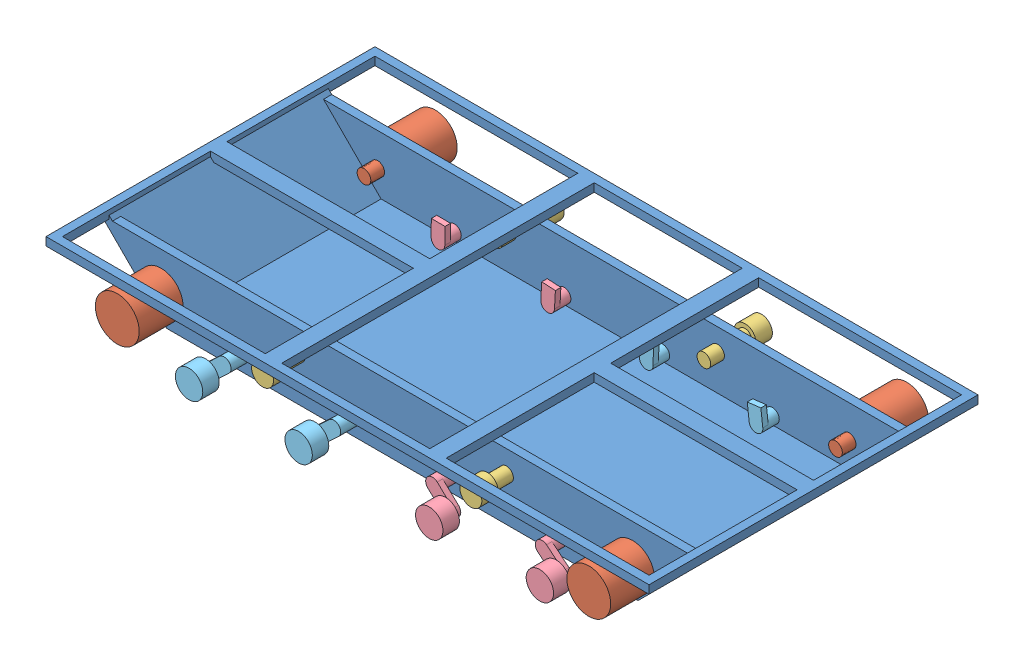
SolidWorks assembly Bodengruppe, configuration Standard. Lengths in mm.
Overall size (1100 159.37 600).
17 component instances, 5 part files, 32 mates.
Components (placement in the parent):
- Bodenwanne-1: Bodenwanne [Standard] at (-44.5526 57.4027 1100.0001) size (1100 135 600)
- Antriebsrolle-1: Antriebsrolle [Standard] at (-424.5526 -2.5973 1260.0001) x (0.031051 -0.999518 0) z (0 0 1) size (80 80 130)
- Antriebsrolle-2: Antriebsrolle [Standard] at (435.4474 -2.5973 1260.0001) x (0.999056 0.043432 0) z (0 0 1) size (80 80 130)
- Antriebsrolle-3: Antriebsrolle [Standard] at (-424.5526 -2.5973 940.0001) x (-0.898197 -0.439592 0) z (0 0 -1) size (80 80 130)
- Antriebsrolle-4: Antriebsrolle [Standard] at (435.4474 -2.5973 940.0001) x (-0.923728 -0.383049 0) z (0 0 -1) size (80 80 130)
- Führungsrolle-1: Führungsrolle [Standard] at (-184.5526 17.4027 1260.0001) x (0.998302 0.05825 0) z (0 0 1) size (40 40 105)
- Führungsrolle-2: Führungsrolle [Standard] at (195.4474 17.4027 1260.0001) x (0.998302 -0.05825 0) z (0 0 1) size (40 40 105)
- Führungsrolle-3: Führungsrolle [Standard] at (195.4474 17.4027 940.0001) x (-0.923728 -0.383049 0) z (0 0 -1) size (40 40 105)
- Führungsrolle-4: Führungsrolle [Standard] at (-184.5526 17.4027 940.0001) x (-0.923728 -0.383049 0) z (0 0 -1) size (40 40 105)
- Laufrolle-Rechts-1: Laufrolle-Rechts [Standard] at (95.4474 -32.5973 1265.0001) x (0.999622 0.027492 0) z (0 0 1) size (65.78 83.28 115)
- Laufrolle-Rechts-2: Laufrolle-Rechts [Standard] at (295.4474 -32.5973 1265.0001) x (0.995459 0.095187 0) z (0 0 1) size (65.78 83.28 115)
- Laufrolle-Rechts-3: Laufrolle-Rechts [Standard] at (-84.5526 -32.5973 935.0001) x (-0.998442 0.055805 0) z (0 0 -1) size (65.78 83.28 115)
- Laufrolle-Rechts-4: Laufrolle-Rechts [Standard] at (-284.5526 -32.5973 935.0001) x (-0.999954 0.009634 0) z (0 0 -1) size (65.78 83.28 115)
- Laufrolle-Links-1: Laufrolle-Links [Standard] at (-284.5526 -32.5973 1265.0001) x (0.999635 -0.027031 0) z (0 0 1) size (65.78 83.28 115)
- Laufrolle-Links-2: Laufrolle-Links [Standard] at (-84.5526 -32.5973 1265.0001) x (0.999467 -0.032641 0) z (0 0 1) size (65.78 83.28 115)
- Laufrolle-Links-3: Laufrolle-Links [Standard] at (95.4474 -32.5973 935.0001) x (-0.999945 0.010485 0) z (0 0 -1) size (65.78 83.28 115)
- Laufrolle-Links-4: Laufrolle-Links [Standard] at (295.4474 -32.5973 935.0001) x (-0.993247 -0.11602 0) z (0 0 -1) size (65.78 83.28 115)
Mates (geometry in assembly coordinates):
- Konzentrisch1: concentric anti-aligned: cylinder of Bodenwanne-1 through (-424.5526 -2.5973 855.0001) axis (0 0 1) radius 12.5; cylinder of Antriebsrolle-1 through (-424.5526 -2.5973 1310.0001) axis (0 0 -1) radius 12.5
- Abstand1: distance = 10 mm anti-aligned: plane of Antriebsrolle-1 through (-424.5526 -2.5973 1310.0001) normal (0 0 -1); plane of Bodenwanne-1 through (555.4474 -62.5973 1300.0001) normal (0 0 1)
- Konzentrisch2: concentric anti-aligned: cylinder of Bodenwanne-1 through (435.4474 -2.5973 855.0001) axis (0 0 1) radius 12.5; cylinder of Antriebsrolle-2 through (435.4474 -2.5973 1310.0001) axis (0 0 -1) radius 12.5
- Abstand2: distance = 10 mm anti-aligned: plane of Antriebsrolle-2 through (435.4474 -2.5973 1310.0001) normal (0 0 -1); plane of Bodenwanne-1 through (555.4474 -62.5973 1300.0001) normal (0 0 1)
- Konzentrisch3: concentric aligned: cylinder of Bodenwanne-1 through (-424.5526 -2.5973 855.0001) axis (0 0 1) radius 12.5; cylinder of Antriebsrolle-3 through (-424.5526 -2.5973 890.0001) axis (0 0 1) radius 12.5
- Abstand3: distance = 10 mm anti-aligned: plane of Antriebsrolle-3 through (-424.5526 -2.5973 890.0001) normal (0 0 1); plane of Bodenwanne-1 through (-544.5526 -62.5973 900.0001) normal (0 0 -1)
- Konzentrisch4: concentric aligned: cylinder of Bodenwanne-1 through (435.4474 -2.5973 855.0001) axis (0 0 1) radius 12.5; cylinder of Antriebsrolle-4 through (435.4474 -2.5973 890.0001) axis (0 0 1) radius 12.5
- Abstand4: distance = 10 mm anti-aligned: plane of Bodenwanne-1 through (-544.5526 -62.5973 900.0001) normal (0 0 -1); plane of Antriebsrolle-4 through (435.4474 -2.5973 890.0001) normal (0 0 1)
- Konzentrisch5: concentric anti-aligned: cylinder of Bodenwanne-1 through (-184.5526 17.4027 855.0001) axis (0 0 1) radius 12.5; cylinder of Führungsrolle-1 through (-184.5526 17.4027 1335.0001) axis (0 0 -1) radius 12.5
- Konzentrisch6: concentric anti-aligned: cylinder of Bodenwanne-1 through (195.4474 17.4027 855.0001) axis (0 0 1) radius 12.5; cylinder of Führungsrolle-2 through (195.4474 17.4027 1335.0001) axis (0 0 -1) radius 12.5
- Konzentrisch7: concentric aligned: cylinder of Bodenwanne-1 through (-184.5526 17.4027 855.0001) axis (0 0 1) radius 12.5; cylinder of Führungsrolle-4 through (-184.5526 17.4027 865.0001) axis (0 0 1) radius 12.5
- Konzentrisch8: concentric aligned: cylinder of Bodenwanne-1 through (195.4474 17.4027 855.0001) axis (0 0 1) radius 12.5; cylinder of Führungsrolle-3 through (195.4474 17.4027 865.0001) axis (0 0 1) radius 12.5
- Abstand5: distance = 35 mm anti-aligned: plane of Führungsrolle-3 through (195.4474 17.4027 865.0001) normal (0 0 1); plane of Bodenwanne-1 through (-544.5526 -62.5973 900.0001) normal (0 0 -1)
- Abstand6: distance = 35 mm anti-aligned: plane of Führungsrolle-4 through (-184.5526 17.4027 865.0001) normal (0 0 1); plane of Bodenwanne-1 through (-544.5526 -62.5973 900.0001) normal (0 0 -1)
- Abstand7: distance = 35 mm anti-aligned: plane of Führungsrolle-2 through (195.4474 17.4027 1335.0001) normal (0 0 -1); plane of Bodenwanne-1 through (555.4474 -62.5973 1300.0001) normal (0 0 1)
- Abstand8: distance = 35 mm anti-aligned: plane of Führungsrolle-1 through (-184.5526 17.4027 1335.0001) normal (0 0 -1); plane of Bodenwanne-1 through (555.4474 -62.5973 1300.0001) normal (0 0 1)
- Konzentrisch9: concentric anti-aligned: cylinder of Bodenwanne-1 through (-284.5526 -32.5973 855.0001) axis (0 0 1) radius 12.5; cylinder of Laufrolle-Links-1 through (-284.5526 -32.5973 1325.0001) axis (0 0 -1) radius 12.5
- Konzentrisch10: concentric anti-aligned: cylinder of Bodenwanne-1 through (-84.5526 -32.5973 855.0001) axis (0 0 1) radius 12.5; cylinder of Laufrolle-Links-2 through (-84.5526 -32.5973 1325.0001) axis (0 0 -1) radius 12.5
- Konzentrisch11: concentric anti-aligned: cylinder of Bodenwanne-1 through (95.4474 -32.5973 855.0001) axis (0 0 1) radius 12.5; cylinder of Laufrolle-Rechts-1 through (95.4474 -32.5973 1325.0001) axis (0 0 -1) radius 12.5
- Konzentrisch12: concentric anti-aligned: cylinder of Bodenwanne-1 through (295.4474 -32.5973 855.0001) axis (0 0 1) radius 12.5; cylinder of Laufrolle-Rechts-2 through (295.4474 -32.5973 1325.0001) axis (0 0 -1) radius 12.5
- Konzentrisch13: concentric aligned: cylinder of Bodenwanne-1 through (-284.5526 -32.5973 855.0001) axis (0 0 1) radius 12.5; cylinder of Laufrolle-Rechts-4 through (-284.5526 -32.5973 875.0001) axis (0 0 1) radius 12.5
- Konzentrisch14: concentric aligned: cylinder of Bodenwanne-1 through (-84.5526 -32.5973 855.0001) axis (0 0 1) radius 12.5; cylinder of Laufrolle-Rechts-3 through (-84.5526 -32.5973 875.0001) axis (0 0 1) radius 12.5
- Konzentrisch15: concentric aligned: cylinder of Bodenwanne-1 through (95.4474 -32.5973 855.0001) axis (0 0 1) radius 12.5; cylinder of Laufrolle-Links-3 through (95.4474 -32.5973 875.0001) axis (0 0 1) radius 12.5
- Konzentrisch16: concentric aligned: cylinder of Bodenwanne-1 through (295.4474 -32.5973 855.0001) axis (0 0 1) radius 12.5; cylinder of Laufrolle-Links-4 through (295.4474 -32.5973 875.0001) axis (0 0 1) radius 12.5
- Abstand9: distance = 25 mm anti-aligned: plane of Laufrolle-Links-1 through (-284.5526 -32.5973 1325.0001) normal (0 0 -1); plane of Bodenwanne-1 through (555.4474 -62.5973 1300.0001) normal (0 0 1)
- Abstand10: distance = 25 mm anti-aligned: plane of Laufrolle-Links-2 through (-84.5526 -32.5973 1325.0001) normal (0 0 -1); plane of Bodenwanne-1 through (555.4474 -62.5973 1300.0001) normal (0 0 1)
- Abstand11: distance = 25 mm anti-aligned: plane of Laufrolle-Rechts-1 through (95.4474 -32.5973 1325.0001) normal (0 0 -1); plane of Bodenwanne-1 through (555.4474 -62.5973 1300.0001) normal (0 0 1)
- Abstand12: distance = 25 mm anti-aligned: plane of Laufrolle-Rechts-2 through (295.4474 -32.5973 1325.0001) normal (0 0 -1); plane of Bodenwanne-1 through (555.4474 -62.5973 1300.0001) normal (0 0 1)
- Abstand13: distance = 25 mm anti-aligned: plane of Laufrolle-Links-4 through (295.4474 -32.5973 875.0001) normal (0 0 1); plane of Bodenwanne-1 through (-544.5526 -62.5973 900.0001) normal (0 0 -1)
- Abstand14: distance = 25 mm anti-aligned: plane of Laufrolle-Links-3 through (95.4474 -32.5973 875.0001) normal (0 0 1); plane of Bodenwanne-1 through (-544.5526 -62.5973 900.0001) normal (0 0 -1)
- Abstand15: distance = 25 mm anti-aligned: plane of Laufrolle-Rechts-3 through (-84.5526 -32.5973 875.0001) normal (0 0 1); plane of Bodenwanne-1 through (-544.5526 -62.5973 900.0001) normal (0 0 -1)
- Abstand16: distance = 25 mm anti-aligned: plane of Laufrolle-Rechts-4 through (-284.5526 -32.5973 875.0001) normal (0 0 1); plane of Bodenwanne-1 through (-544.5526 -62.5973 900.0001) normal (0 0 -1)
